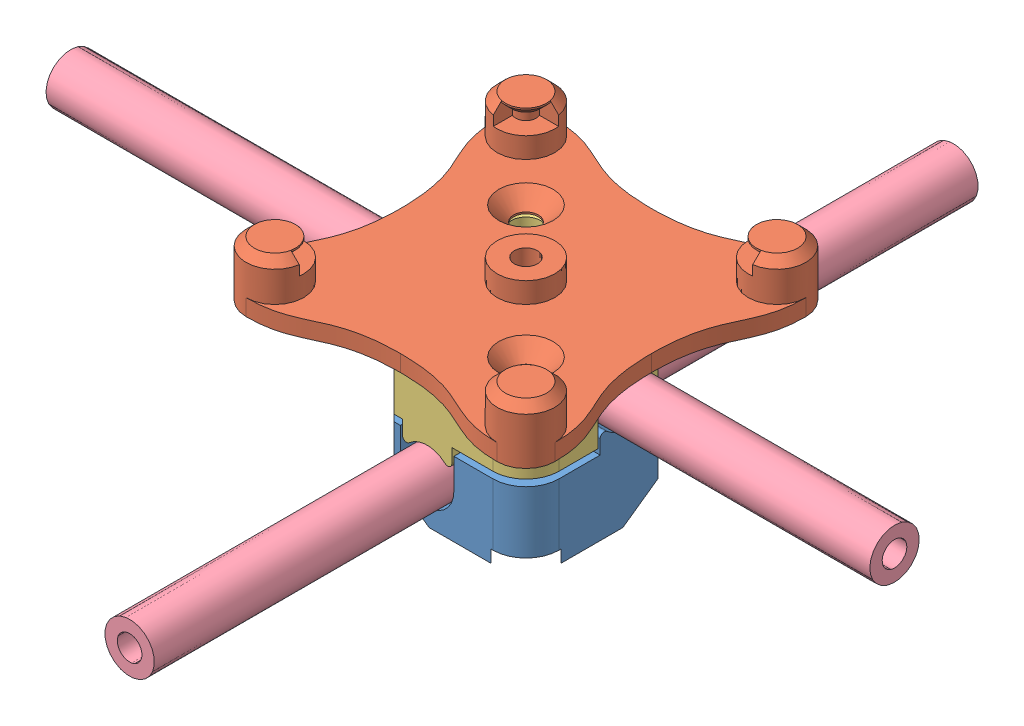
SolidWorks assembly 装配体1, configuration 默认. Lengths in mm.
Overall size (100 25.5 100).
5 component instances, 4 part files, 8 mates.
Components (placement in the parent):
- FrameHolder_tail-1: FrameHolder_tail [默认] at (0.7673 -6.1866 24) size (24 12.2 24)
- FrameHolder_mount-1: FrameHolder_mount [默认] at (0.7673 12.6134 24) size (37.48 6.7 37.48)
- FrameHolder_top-1: FrameHolder_top [默认] at (0.7673 12.6134 24) x (0 0 -1) z (-1 0 0) size (24 10.2 24)
- Tube_4x6x100-1: Tube_4x6x100 [默认] at (0.7673 0.1134 -27.8911) x (-0.918223 -0.396064 0) z (-0.396064 0.918223 0) size (6 100 6)
- Tube_4x6x100-2: Tube_4x6x100 [默认] at (45.5049 8.3134 24) x (0 0.039539 0.999218) z (0 -0.999218 0.039539) size (6 100 6)
Mates (geometry in assembly coordinates):
- 同心1: concentric: cylinder of assembly; cylinder of assembly; cylinder of FrameHolder_tail-1 through (-7.2327 -6.1866 16) axis (0 1 0) radius 1.75; cylinder of FrameHolder_top-1 through (-7.2327 12.6134 16) axis (0 -1 0) radius 1.75
- 同心2: concentric: cylinder of assembly; cylinder of assembly; cylinder of FrameHolder_tail-1 through (8.7673 -6.1866 32) axis (0 1 0) radius 1.75; cylinder of FrameHolder_top-1 through (8.7673 12.6134 32) axis (0 -1 0) radius 1.75
- 同心3: concentric: cylinder of assembly; cylinder of assembly; cylinder of FrameHolder_top-1 through (-7.2327 12.6134 16) axis (0 -1 0) radius 1.75; cylinder of FrameHolder_mount-1 through (-7.2327 12.6134 16) axis (0 1 0) radius 1.5
- 同心4: concentric: cylinder of assembly; cylinder of assembly; cylinder of FrameHolder_top-1 through (8.7673 12.6134 32) axis (0 -1 0) radius 1.75; cylinder of FrameHolder_mount-1 through (8.7673 12.6134 32) axis (0 1 0) radius 1.5
- 重合1: coincident: plane of assembly; plane of assembly; plane of FrameHolder_mount-1 through (0.7673 12.6134 24) normal (0 -1 0); plane of FrameHolder_top-1 through (0.7673 12.6134 24) normal (0 1 0)
- 同心5: concentric: cylinder of assembly; cylinder of assembly; cylinder of FrameHolder_tail-1 through (0.7673 0.1134 12) axis (0 0 1) radius 3.25; cylinder of Tube_4x6x100-1 through (0.7673 0.1134 72.1089) axis (0 0 -1) radius 3
- 同心6: concentric: cylinder of assembly; cylinder of assembly; cylinder of FrameHolder_top-1 through (12.7673 8.3134 24) axis (-1 0 0) radius 3.25; cylinder of Tube_4x6x100-2 through (-54.4951 8.3134 24) axis (1 0 0) radius 3
- 同心7: concentric: cylinder of assembly; cylinder of assembly; cylinder of FrameHolder_tail-1 through (-2.4827 8.3134 24) axis (-1 0 0) radius 3.25; cylinder of Tube_4x6x100-2 through (-54.4951 8.3134 24) axis (1 0 0) radius 3
